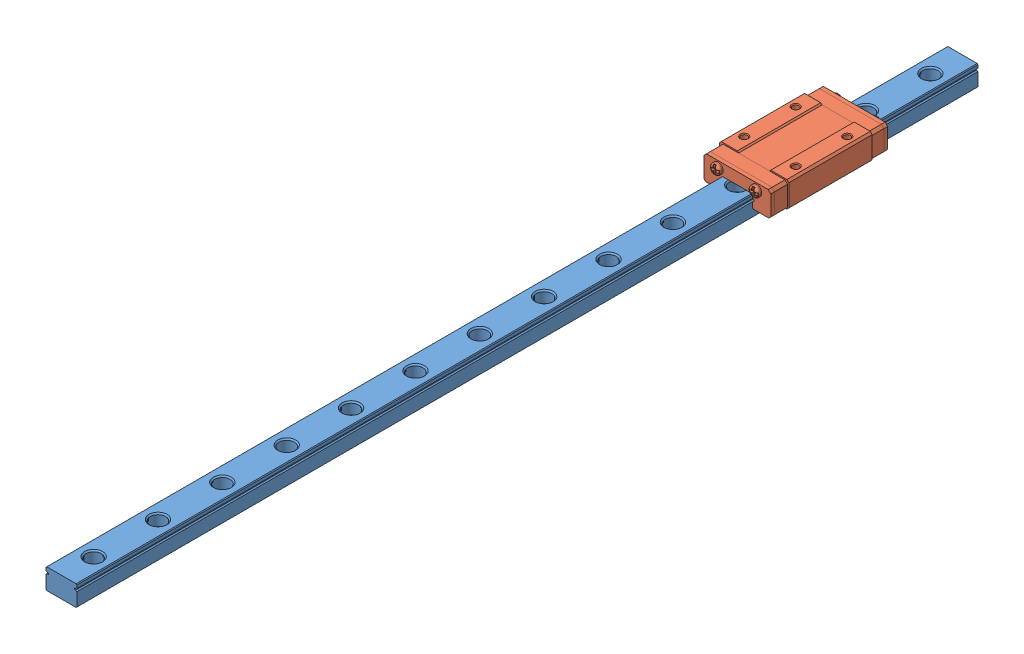
SolidWorks assembly MGN12H-400, configuration 預設. Lengths in mm.
Overall size (27 13 350).
2 component instances, 2 part files, 4 mates.
Components (placement in the parent):
- MGNR12 400mm-2: MGNR12 400mm [Default] at origin size (12 8 350)
- MGN12H-1: MGN12H [Default] at (0 -4 64.7955) size (27 10 48.55)
Mates (geometry in assembly coordinates):
- 重合/共線/共點2: coincident anti-aligned: plane of MGN12H-1 through (-6 4 94.1955) normal (0 -1 0); plane of MGNR12 400mm-2 through (-6 4 350) normal (0 1 0)
- 同軸心3: concentric anti-aligned: cylinder of MGN12H-1 through (6 2 42.0955) axis (0 0 1) radius 0.559; cylinder of MGNR12 400mm-2 through (6 2 350) axis (0 0 -1) radius 0.559
- 同軸心4: concentric anti-aligned: cylinder of MGN12H-1 through (-6 2 43.5955) axis (0 0 1) radius 0.559; cylinder of MGNR12 400mm-2 through (-6 2 350) axis (0 0 -1) radius 0.559
- 重合/共線/共點3: coordinate: point of MGNR12 400mm-2
